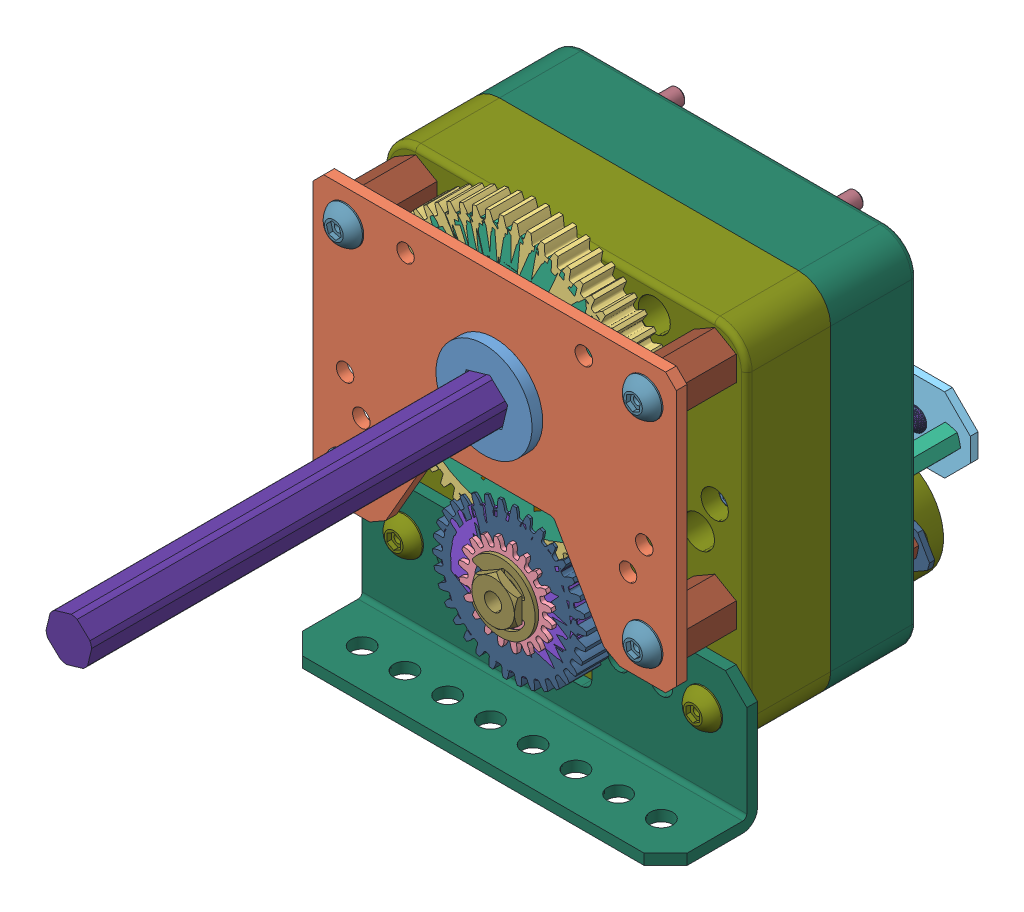
SolidWorks assembly VEXPro 2 CIM Ballshifter, configuration Default. Lengths in mm.
Overall size (152.4 156.19 242.5).
107 component instances, 60 part files, 0 mates.
Components (placement in the parent):
- 217-2733-001 Rev2-1: 217-2733-001 Rev2 [Default] at (0 53.4162 12.0523) x (0 0 1) z (0.878299 0.478111 0) size (7.11 24.61 24.61)
- 217-2733-001 Rev2-2: 217-2733-001 Rev2 [Default] at (0 53.4162 -17.6911) x (0 0 -1) z (0.971421 0.237365 0) size (7.11 24.61 24.61)
- 217-2731-001 Rev2-1: 217-2731-001 Rev2 [Default] at (0 0 -25.6286) x (0.99998 -0.006249 0) z (-0.006249 -0.99998 0) size (31.12 7.94 31.12)
- 217-2789-001 Rev2-1: 217-2789-001 Rev2 [Default] at (0 0 17.6784) x (0 0 -1) z (0.997427 0.071687 0) size (11.1 38.4 38.4)
- 217-2788-001 Rev3_57155K375-1: 217-2788-001 Rev3_57155K375 [Default] at (0 0 -46.8376) x (0.743593 0.668633 0) z (0 0 1) size (9.53 9.53 3.17)
- 217-2428-012 Rev2-1: 217-2428-012 Rev2 [Default] at (0 0 -66.0019) size (63.5 22.23 2.29)
- 217-2428-027 Rev1_97414A630-1: 217-2428-027 Rev1_97414A630 [Default] at (0 0 -48.7426) x (0 0 -1) z (-0.538463 -0.842649 0) (suppressed, hidden)
- 217-2428-005 Rev1-1: 217-2428-005 Rev1 [Default] at (25.4 0 -44.6659) x (-0.968533 0.248884 0) z (0.248884 0.968533 0) size (7.33 38.98 6.35)
- 217-2428-005 Rev1-2: 217-2428-005 Rev1 [Default] at (-25.4 0 -44.6659) x (0.661665 -0.7498 0) z (-0.7498 -0.661665 0) size (7.33 38.98 6.35)
- SCREW-832-0375-1: SCREW-832-0375 [Default] at (25.4 0 -68.2117) x (0 0 1) z (-0.875404 0.483392 0) size (11.73 7.92 7.92)
- SCREW-832-0375-2: SCREW-832-0375 [Default] at (-25.4 0 -68.2117) x (0 0 1) z (-0.875404 0.483392 0) size (11.73 7.92 7.92)
- SCREW-832-0375-3: SCREW-832-0375 [Default] at (25.4 0 -20.2311) x (0 0 -1) z (1 0 0) size (11.73 7.92 7.92)
- SCREW-832-0375-4: SCREW-832-0375 [Default] at (-25.4 0 -20.2311) x (0 0 -1) z (0.999351 0.036025 0) size (11.73 7.92 7.92)
- SBS1_SBS-0632-0250-1: SBS1_SBS-0632-0250 [Default] at (15.494 0 -61.8617) x (0 0 -1) z (0.854303 -0.519775 0) size (8.57 6.68 6.65)
- SBS1_SBS-0632-0250-2: SBS1_SBS-0632-0250 [Default] at (-15.494 0 -61.8617) x (0 0 -1) z (0.854303 -0.519775 0) size (8.57 6.68 6.65)
- 217-2428-016 Rev3_Spur01-1: 217-2428-016 Rev3_Spur01 [Default] at (0 0 -29.2807) x (0.982225 0.187706 0) z (0 0 1) size (40.67 40.74 13.32)
- 217-2428-019 Rev1-1: 217-2428-019 Rev1 [Default] at (12.7 -21.997 -46.2407) x (0.866025 0.5 0) z (0 0 1) size (50.8 19.05 1.57)
- 217-2428-006 Rev1-1: 217-2428-006 Rev1 [Default] at (32.079 -14.2875 -35.1409) x (-0.95139 -0.30799 0) z (-0.30799 0.95139 0) size (7.33 19.93 6.35)
- 217-2428-006 Rev1-2: 217-2428-006 Rev1 [Default] at (-3.6662 -34.925 -35.1409) x (-0.054239 0.998528 0) z (0.998528 0.054239 0) size (7.33 19.93 6.35)
- SCREW-832-0375-5: SCREW-832-0375 [Default] at (32.079 -14.2875 -20.2311) x (0 0 -1) z (0.980613 0.195955 0) size (11.73 7.92 7.92)
- SCREW-832-0375-6: SCREW-832-0375 [Default] at (-3.6662 -34.925 -20.2311) x (0 0 -1) z (-0.826375 -0.56312 0) size (11.73 7.92 7.92)
- SCREW-832-0375-7: SCREW-832-0375 [Default] at (-3.6662 -34.925 -48.4505) x (0 0 1) z (0.948865 0.315681 0) size (11.73 7.92 7.92)
- SCREW-832-0375-8: SCREW-832-0375 [Default] at (32.079 -14.2875 -48.4505) x (0 0 1) z (-0.875404 0.483392 0) size (11.73 7.92 7.92)
- 217-2428-017 Rev2-1: 217-2428-017 Rev2 [Default] at (12.7 -21.997 -29.2807) x (0.976331 0.216282 0) z (0 0 1) size (14.73 14.73 7.37)
- SBS1_SBS1032-0500ZC-1: SBS1_SBS1032-0500ZC [Default] at (-39.6321 27.2942 -19.8755) x (0 0 -1) z (0.878202 0.478289 0) size (15.78 9.29 9.24)
- SBS1_SBS1032-0500ZC-2: SBS1_SBS1032-0500ZC [Default] at (-26.4841 76.3632 -19.8755) x (0 0 -1) z (0.751237 -0.660033 0) size (15.78 9.29 9.24)
- 217-2614-001_12t-1: 217-2614-001_12t [Default] at (-33.0581 51.8287 -4.1095) x (-0.258819 -0.965926 0) z (0 0 1) size (18.29 18.29 19)
- 217-2761-001 rev1-1: 217-2761-001 rev1 [Default] at (-29.3876 50.8452 -9.5159) x (0.258819 0.965926 0) z (0 0 1) (suppressed, hidden)
- SBS1_SBS1032-0500ZC-3: SBS1_SBS1032-0500ZC [Default] at (39.6321 27.2942 -19.8755) x (0 0 -1) z (0.618676 -0.785646 0) size (15.78 9.29 9.24)
- SBS1_SBS1032-0500ZC-4: SBS1_SBS1032-0500ZC [Default] at (26.4841 76.3632 -19.8755) x (0 0 -1) z (0.996655 0.081722 0) size (15.78 9.29 9.24)
- 217-2761-001 rev1-2: 217-2761-001 rev1 [Default] at (29.3876 50.8452 -9.5159) x (-0.258819 0.965926 0) z (0 0 1) (suppressed, hidden)
- 217-2614-001_12t-2: 217-2614-001_12t [Default] at (33.0581 51.8287 -4.1095) x (-0.258819 0.965926 0) z (0 0 1) size (18.29 18.29 19)
- 217-2428-001 Rev1-1: 217-2428-001 Rev1 [Default] at (0 53.4162 -25.6159) size (107.95 127.51 28.8)
- 217-2428-002 Rev2-1: 217-2428-002 Rev2 [Default] at (0 53.4162 24.9301) x (-1 0 0) z (0 0 -1) size (107.95 127.51 28.11)
- 217-2703-001-1: 217-2703-001 [Default] at (0 53.4162 4.5339) x (-0.958428 0.285334 0) z (0 0 1) size (33.29 33.29 12.65)
- 217-2707-001_40t-1: 217-2707-001_40t [Default] at (0 53.4162 -8.1661) x (0.726321 0.687356 0) z (0 0 1) size (53.62 53.62 12.65)
- SBS1_SBS0832-1750SS-1: SBS1_SBS0832-1750SS [Default] at (-44.45 36.7075 21.4249) x (0 0 -1) z (0.052618 -0.998615 0) size (47.11 8.02 7.99)
- SBS1_SBS0832-1750SS-2: SBS1_SBS0832-1750SS [Default] at (44.45 36.7075 21.4249) x (0 0 -1) z (0.699378 -0.714752 0) size (47.11 8.02 7.99)
- Nylock Nut_NNY2520-ZC-1: Nylock Nut_NNY2520-ZC [Default] at (44.45 -14.0925 -17.7546) x (0 1 0) z (0 0 -1) size (12.85 11.89 7.62)
- Nylock Nut_NNY2520-ZC-2: Nylock Nut_NNY2520-ZC [Default] at (44.45 74.8075 -17.7546) x (0 1 0) z (0 0 -1) size (12.85 11.89 7.62)
- 217-2428-004 Rev3-1: 217-2428-004 Rev3 [Default] at (0 53.4162 -2.8448) x (0.97269 0.232108 0) z (0 0 1) size (11 9.53 43.92)
- 217-2428-021 Rev1-1: 217-2428-021 Rev1 [Default] at (0 53.4162 -16.1036) x (0.999182 0.040427 0) z (0 0 1) size (15.88 15.88 3.17)
- 217-2428-029 Rev1-1: 217-2428-029 Rev1 [Default] at (0 53.4162 11.4173) size (15.88 15.88 1.12)
- Nylock 8-32-1: Nylock 8-32 [Default] at (44.45 36.7075 -19.2659) x (0.254216 0.967147 0) z (-0.967147 0.254216 0) size (10.2 4.9 8.12)
- Nylock 8-32-2: Nylock 8-32 [Default] at (-44.45 36.7075 -19.2659) x (0.948441 0.316954 0) z (-0.316954 0.948441 0) size (10.2 4.9 8.12)
- 217-2793-001 Rev1-1: 217-2793-001 Rev1 [Default] at (0 0 -25.5778) x (0 -1 0) z (0 0 1) size (82.39 82.39 97.02)
  - 217-2428-008 Rev2-1: 217-2428-008 Rev2 [Default] at (0 0 10.2679) size (31.75 31.75 1.59)
  - 217-2428-028 Rev1_97633A250-1: 217-2428-028 Rev1_97633A250 [Default] at (0 0 37.1221) x (0 0 1) z (0.9357 -0.352797 0) size (1.07 23.39 21.18)
  - 217-2709-101 Rev1-1: 217-2709-101 Rev1 [Default] at (0 0 20.7137) x (-0.998987 -0.044993 0) z (0 0 -1) size (58.74 58.74 12.7)
    - 217-2428-022 Rev1-1: 217-2428-022 Rev1 [Default] at origin size (28.57 28.57 6.1)
    - 217-2709-001_44t Steel-1: 217-2709-001_44t Steel [Default] at (0 0 3.302) size (58.74 58.74 11.11)
  - 217-2713-101 Rev1-1: 217-2713-101 Rev1 [Default] at (0 0 30.1117) x (-0.998987 -0.044993 0) z (0 0 -1) size (78.91 78.91 12.7)
    - 217-2428-022 Rev1-1: 217-2428-022 Rev1 [Default] at (0 0 -3.302) size (28.57 28.57 6.1)
    - 217-2713-001_60t Steel-1: 217-2713-001_60t Steel [Default] at origin size (78.91 78.91 11.11)
  - 217-2791-001 Rev2-1: 217-2791-001 Rev2 [Default] x (-1 0 0) z (0 0 1) size (22.23 22.23 97.02)
    - 217-2791-002 Rev2-1: 217-2791-002 Rev2 [Default] at (0 0 53.467) x (0 -1 0) z (0 0 1) size (12.7 16.13 36.96)
    - 217-2790-003 Rev2-1: 217-2790-003 Rev2 [Default] at origin size (22.23 22.23 55.94)
    - 217-2790-004 Rev2-1: 217-2790-004 Rev2 [Default] at (0 0 14.5022) x (0.877055 0.48039 0) z (0 0 1) size (11.68 11.68 55)
  - 217-2428-007 Rev1-1: 217-2428-007 Rev1 [Default] at (6.275 0 14.2494) x (0.477673 -0.652226 -0.588582) z (0.408838 -0.427964 0.806039) size (6.35 6.35 6.35)
  - 217-2428-007 Rev1-2: 217-2428-007 Rev1 [Default] at (6.275 0 26.9494) x (-0.162331 -0.978398 0.128005) z (0.857281 -0.204076 -0.472676) size (6.35 6.35 6.35)
  - 217-2428-007 Rev1-3: 217-2428-007 Rev1 [Default] at (-3.1375 5.4343 14.2494) x (0.326008 0.73979 -0.588582) z (0.166208 0.568046 0.806039) size (6.35 6.35 6.35)
  - 217-2428-007 Rev1-4: 217-2428-007 Rev1 [Default] at (-3.1375 -5.4343 14.2494) x (-0.803681 -0.087564 -0.588582) z (-0.575047 -0.140083 0.806039) size (6.35 6.35 6.35)
  - 217-2428-007 Rev1-5: 217-2428-007 Rev1 [Default] at (-3.1375 5.4343 26.9494) x (0.928483 0.348617 0.128005) z (-0.251905 0.844465 -0.472676) size (6.35 6.35 6.35)
  - 217-2428-007 Rev1-6: 217-2428-007 Rev1 [Default] at (-3.1375 -5.4343 26.9494) x (-0.766153 0.629782 0.128005) z (-0.605376 -0.640389 -0.472676) size (6.35 6.35 6.35)
- 217-2000-1: 217-2000 [Default] at (33.0581 51.8287 -25.6159) x (0 0 -1) z (0.965926 0.258819 0) (suppressed, hidden)
- 217-2000-2: 217-2000 [Default] at (-33.0581 51.8287 -25.6159) x (0 0 -1) z (-0.965926 0.258819 0) (suppressed, hidden)
- Grahill Encoder-1: Grahill Encoder [Default] at (12.7 -21.997 -41.7957) x (0.902286 -0.431138 0) z (0.431138 0.902286 0) size (31.75 31.12 31.75)
- 217-2617-003 Rev2-1: 217-2617-003 Rev2 [Default] at (0 53.4162 96.2376) x (-0.959408 -0.282023 0) z (0 0 1) size (13.74 12.7 152.4)
- 217-3109-001 Rev1-1: 217-3109-001 Rev1 [Default] at (0 53.4162 23.5648) x (0 0 -1) z (-0.999944 0.010604 0) size (7.94 28.57 28.57)
- 217-2734-001 Rev3-1: 217-2734-001 Rev3 [Default] at (0 53.4162 49.0601) x (0.235465 0.971883 0) z (-0.971883 0.235465 0) size (31.12 7.94 31.12)
- 217-2617-001 Rev4-1: 217-2617-001 Rev4 [Default] at (0 30.3575 42.7101) size (152.4 82.55 3.17)
- 217-2715-002 Rev1_64t-1: 217-2715-002 Rev1_64t [Default] at (0 53.4162 36.0366) x (-0.68986 -0.723943 0) z (0 0 1) size (84.3 84.3 12.65)
- 217-2702-001_20t-1: 217-2702-001_20t [Default] at (0 0 36.6903) x (0.625762 -0.780014 0) z (0 0 1) size (28.2 28.2 12.65)
- 217-2704-001_24-1: 217-2704-001_24 [Default] at (0 0 35.0841) x (0.993482 -0.113989 0) z (0 0 1) size (33.29 33.29 12.65)
- 217-2714-002 Rev1_60t-1: 217-2714-002 Rev1_60t [Default] at (0 53.4162 36.0366) x (-0.68986 -0.723943 0) z (0 0 1) size (78.95 78.95 12.65)
- 217-3221-002 Rev1-1: 217-3221-002 Rev1 [Default] at (0 53.4162 36.0239) x (-0.68986 -0.723943 0) z (0 0 1) size (71.39 71.45 12.62)
- 217-2705-001_30t-1: 217-2705-001_30t [Default] at (0 0 36.6903) size (41.01 41.12 12.65)
- 217-2712-002 Rev1_50t-1: 217-2712-002 Rev1_50t [Default] at (0 53.4162 36.0366) x (0.971883 -0.235465 0) z (0 0 1) size (66.7 66.76 12.65)
- 217-2706-001_34t-1: 217-2706-001_34t [Default] at (0 0 36.6903) x (0.5 0.866025 0) z (0 0 1) size (46.46 46.56 12.65)
- 217-2617-002 Rev1_91780A359-1: 217-2617-002 Rev1_91780A359 [Default] at (-44.45 74.8075 30.0101) size (12.7 14.66 25.4)
- 217-2617-002 Rev1_91780A359-2: 217-2617-002 Rev1_91780A359 [Default] at (44.45 74.8075 30.0101) x (-0.5 -0.866025 0) z (0 0 -1) size (12.7 14.66 25.4)
- 217-2617-002 Rev1_91780A359-3: 217-2617-002 Rev1_91780A359 [Default] at (-44.45 11.3075 30.0101) size (12.7 14.66 25.4)
- 217-2617-002 Rev1_91780A359-4: 217-2617-002 Rev1_91780A359 [Default] at (44.45 11.3075 30.0101) size (12.7 14.66 25.4)
- 217-2617-004 Rev1_97431A340_grv-1: 217-2617-004 Rev1_97431A340_grv [Default] at (0 0 43.5483) x (0 0 1) z (-1 0 0) size (1.07 20.42 18.58)
- 217-2617-004 Rev1_97431A340_grv-2: 217-2617-004 Rev1_97431A340_grv [Default] at (0 53.4162 29.1786) x (0 0 1) z (-1 0 0) size (1.07 20.42 18.58)
- SBS1_SBS2520-1750-1: SBS1_SBS2520-1750 [Default] at (44.45 11.3075 -18.1737) x (0 0 1) z (-0.961255 0.27566 0) size (48.48 11.22 11.17)
- SBS1_SBS2520-1750-2: SBS1_SBS2520-1750 [Default] at (44.45 74.8075 -18.1737) x (0 0 1) z (-0.983108 -0.183029 0) size (48.48 11.22 11.17)
- SBS1_SBS2520-1750-3: SBS1_SBS2520-1750 [Default] at (-44.45 74.8075 -18.1737) x (0 0 1) z (-0.878539 0.47767 0) size (48.48 11.22 11.17)
- SBS1_SBS2520-1750-4: SBS1_SBS2520-1750 [Default] at (-44.45 11.3075 -18.1737) x (0 0 1) z (-0.805318 -0.592843 0) size (48.48 11.22 11.17)
- SBS1_SBS2520-0625ZC-1: SBS1_SBS2520-0625ZC [Default] at (-44.45 74.8075 49.2379) x (0 0 -1) z (0.963378 0.268146 0) size (19.57 11.22 11.17)
- SBS1_SBS2520-0625ZC-2: SBS1_SBS2520-0625ZC [Default] at (-44.45 11.3075 49.2379) x (0 0 -1) z (-0.232142 -0.972682 0) size (19.57 11.22 11.17)
- SBS1_SBS2520-0625ZC-3: SBS1_SBS2520-0625ZC [Default] at (44.45 74.8075 49.2379) x (0 0 -1) z (-0.560912 -0.827875 0) size (19.57 11.22 11.17)
- SBS1_SBS2520-0625ZC-4: SBS1_SBS2520-0625ZC [Default] at (44.45 11.3075 49.2379) x (0 0 -1) z (0.367215 0.930136 0) size (19.57 11.22 11.17)
- 217-2778-001 Rev2_NCQ8A075-050M-1: 217-2778-001 Rev2_NCQ8A075-050M [Default] at (0 0 -79.4639) x (0.71017 0.704031 0) z (0 0 1) size (31.75 33.34 52.34) (suppressed, hidden)
- 217-2428-024 Rev2-1: 217-2428-024 Rev2 [Default] at (0 -39.4925 40.1701) x (-1 0 0) z (0 1 0) size (114.3 27.31 38.1)
- Nylock Nut_NNY2520-ZC-3: Nylock Nut_NNY2520-ZC [Default] at (-44.45 -14.0925 -17.7546) x (0 1 0) z (0 0 -1) size (12.85 11.89 7.62)
- SBS1_SBS2520-2000ZC-1: SBS1_SBS2520-2000ZC [Default] at (-44.45 -14.0925 31.4579) x (0 0 -1) z (1 0 0) size (54.83 11.22 11.17)
- SBS1_SBS2520-2000ZC-2: SBS1_SBS2520-2000ZC [Default] at (44.45 -14.0925 31.4579) x (0 0 -1) z (1 0 0) size (54.83 11.22 11.17)
- 217-2428-032 Rev1-1: 217-2428-032 Rev1 [Default] at (0 0 -53.8734) x (0.806241 -0.591587 0) z (0 0 -1) size (18.09 11.02 22.68)
- 217-2428-032 Rev1-2: 217-2428-032 Rev1 [Default] at (0 0 -53.8734) x (-0.806241 0.591587 0) z (0 0 -1) size (18.09 11.02 22.68)
- 217-2778-NCQ8A075-050M_1032_Nut_90545A111-1: 217-2778-NCQ8A075-050M_1032_Nut_90545A111 [Default] at (0 0 -56.2229) x (-0.806241 0.591587 0) z (0 0 -1) (suppressed, hidden)
- 91251A107_91251A107_1-1: 91251A107_91251A107_1 [Default] at (2.342 -7.8426 -50.6984) x (-0.572568 0.420127 0.704031) z (-0.591587 -0.806241 0) (suppressed, hidden)
- 91251A107_91251A107_1-2: 91251A107_91251A107_1 [Default] at (-2.342 7.8426 -50.6984) x (-0.768326 0.563766 -0.303056) z (0.591587 0.806241 0) (suppressed, hidden)
- 217-2428-023 Rev1_9714K3-1: 217-2428-023 Rev1_9714K3 [Default] at (0 0 10.8839) x (0.147022 0.989133 0) z (0.989133 -0.147022 0) size (26.82 4.09 28.39)
- 217-2428-027 Rev1_97414A630-2: 217-2428-027 Rev1_97414A630 [Default] at (0 0 -44.9326) x (0 0 -1) z (0.823209 -0.567739 0) (suppressed, hidden)
- SCREW-632-0250-1: SCREW-632-0250 [Default] at (-15.494 0 -61.8617) x (0 0 -1) z (1 0 0) size (8.2 6.59 6.59)
- SCREW-632-0250-2: SCREW-632-0250 [Default] at (15.494 0 -61.8617) x (0 0 -1) z (1 0 0) size (8.2 6.59 6.59)
